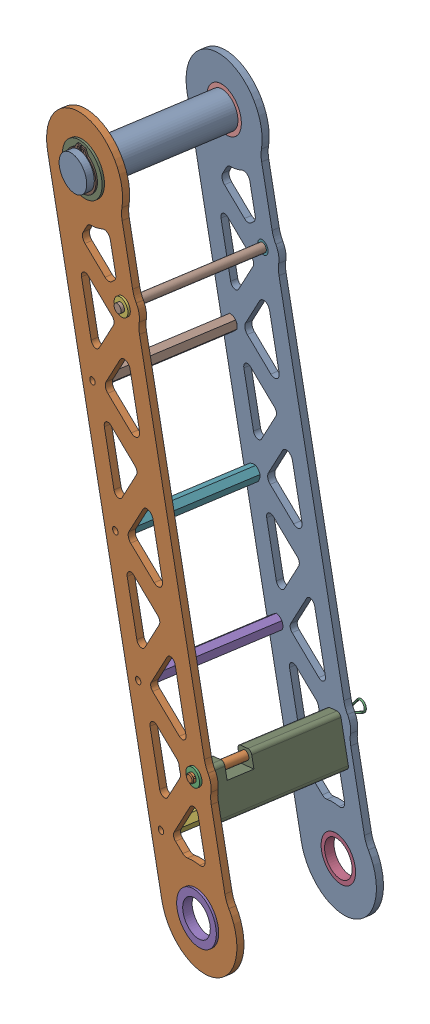
SolidWorks assembly UOR23-ARM-2-A-005_Arm, configuration Default. Lengths in mm.
Overall size (202.51 521.96 130.33).
21 component instances, 9 part files, 41 mates.
Components (placement in the parent):
- UOR23-ARM-2-P-001-1: UOR23-ARM-2-P-001 [Default] at (-90.7389 342.9702 -136.8786) x (-0.230879 0.972312 -0.036117) z (0.154553 0 -0.987984) size (520 70 4.76)
- UOR23-ARM-2-P-001-2: UOR23-ARM-2-P-001 [Default] at (-105.2152 342.9702 -44.3384) x (-0.230879 0.972312 -0.036117) z (0.154553 0 -0.987984) size (520 70 4.76)
- UOR23-ARM-2-P-005-1: UOR23-ARM-2-P-005 [6389K627] at (-56.9045 215.9378 -35.1742) x (-0.987956 0.007597 -0.154549) z (-0.007506 -0.999971 -0.001174) size (12.7 6.35 12.7)
- UOR23-ARM-2-P-005-2: UOR23-ARM-2-P-005 [6389K627] at (-41.2014 215.9378 -135.5565) x (0.894742 -0.424081 0.139967) z (-0.418986 -0.905624 -0.065543) size (12.7 6.35 12.7)
- 91780A086_Female Threaded Hex Standoff-1: 91780A086_Female Threaded Hex Standoff [91780A086] at (-100.8459 249.6199 -93.4658) x (0.375473 0.92497 0.058736) z (-0.154553 0 0.987984) size (9.53 11 89.52)
- 91780A086_Female Threaded Hex Standoff-2: 91780A086_Female Threaded Hex Standoff [91780A086] at (-80.0668 162.1119 -90.2153) x (0.139737 -0.989947 0.021859) z (0.154553 0 -0.987984) size (9.53 11 89.52)
- 91780A086_Female Threaded Hex Standoff-3: 91780A086_Female Threaded Hex Standoff [91780A086] at (-121.625 337.128 -96.7164) x (0.267 -0.962791 0.041768) z (0.154553 0 -0.987984) size (9.53 11 89.52)
- 91780A086_Female Threaded Hex Standoff-4: 91780A086_Female Threaded Hex Standoff [91780A086] at (-142.4041 424.6361 -99.9669) x (0.260385 0.964645 0.040733) z (0.154553 0 -0.987984) size (9.53 11 89.52)
- UOR23-ARM-2-P-007-1: UOR23-ARM-2-P-007 [6389K559] at (-157.4084 561.7403 -50.8963) x (-0.232229 -0.971982 -0.036328) z (0.960303 -0.235054 0.150223) size (36.51 6.35 36.51)
- UOR23-ARM-2-P-007-2: UOR23-ARM-2-P-007 [6389K559] at (-141.7053 561.7403 -151.2787) x (0.987521 0.030636 0.154481) z (0.030268 -0.999531 0.004735) size (36.51 6.35 36.51)
- 98410A133_External Retaining Ring-1: 98410A133_External Retaining Ring [98410A133] at (-157.4908 561.7403 -50.3693) x (-0.154553 0 0.987984) z (-0.987984 0 -0.154553) size (1.07 30.68 28.04)
- 98410A133_External Retaining Ring-2: 98410A133_External Retaining Ring [98410A133] at (-141.6228 561.7403 -151.8056) x (-0.154553 0 0.987984) z (-0.987984 0 -0.154553) size (1.07 30.68 28.04)
- UOR23-ARM-2-P-006-1: UOR23-ARM-2-P-006 [1346K38] at (-187.8474 561.7403 143.6857) x (-0.913412 0.381132 -0.142888) z (0.154553 0 -0.987984) size (25.4 25.4 114.1)
- UOR23-ARM-2-P-008-1: UOR23-ARM-2-P-008 [1327K68] at (-10.1532 215.9378 -334.0329) x (0.513647 -0.854231 0.080351) z (-0.154553 0 0.987984) size (6.35 6.35 106.22)
- 92375A410_Hairpin Cotter Pin-1: 92375A410_Hairpin Cotter Pin [92375A410] at (-40.3363 220.81 -136.2244) x (-0.164223 0.016127 0.986291) z (-0.843967 -0.519894 -0.132024) size (1.19 9.74 41.27)
- UOR23-ARM-2-P-007-3: UOR23-ARM-2-P-007 [6389K559] at (-37.8097 124.2 -135.026) x (-0.957866 -0.245033 -0.149842) z (-0.242089 0.969515 -0.037871) size (36.51 6.35 36.51)
- UOR23-ARM-2-P-007-4: UOR23-ARM-2-P-007 [6389K559] at (-53.5128 124.2 -34.6436) x (0.138917 0.990066 0.021731) z (-0.978169 0.140606 -0.153018) size (36.51 6.35 36.51)
- UOR23-ARM-2-P-005-3: UOR23-ARM-2-P-005 [6389K627] at (-122.1279 490.6159 -45.3772) x (-0.969764 -0.191163 -0.151703) z (0.188866 -0.981558 0.029545) size (12.7 6.35 12.7)
- UOR23-ARM-2-P-005-4: UOR23-ARM-2-P-005 [6389K627] at (-106.4248 490.6159 -145.7596) x (0.656685 -0.747135 0.102727) z (-0.738158 -0.664672 -0.115472) size (12.7 6.35 12.7)
- UOR23-ARM-2-P-008-2: UOR23-ARM-2-P-008 [1327K68] at (-153.1761 490.6159 153.0991) x (0.663492 0.740949 0.103792) z (0.154553 0 -0.987984) size (6.35 6.35 106.22)
- UOR23-ARM-2-P-014-1: UOR23-ARM-2-P-014 [Default] at (-41.501 185.2495 -129.1729) x (0.960629 0.233687 0.150274) z (-0.154553 0 0.987984) size (13 35 88.9)
Mates (geometry in assembly coordinates):
- Concentric27: concentric aligned: circle of UOR23-ARM-2-P-001-1; circle of UOR23-ARM-2-P-001-2
- Coincident203: coincident anti-aligned: plane of UOR23-ARM-2-P-001-2 through (-53.2675 124.2 -36.212) normal (-0.154553 0 0.987984); plane of UOR23-ARM-2-P-005-1 through (-56.6592 215.9378 -36.7426) normal (0.154553 0 -0.987984)
- Concentric207: concentric aligned: circle of UOR23-ARM-2-P-001-2; circle of UOR23-ARM-2-P-005-1
- Coincident197: coincident anti-aligned: plane of UOR23-ARM-2-P-001-1 through (-38.055 124.2 -133.4575) normal (0.154553 0 -0.987984); plane of UOR23-ARM-2-P-005-2 through (-41.4468 215.9378 -133.9881) normal (-0.154553 0 0.987984)
- Concentric200: concentric aligned: circle of UOR23-ARM-2-P-001-1; circle of UOR23-ARM-2-P-005-2
- Concentric197: concentric aligned: circle of UOR23-ARM-2-P-001-1; circle of 91780A086_Female Threaded Hex Standoff-1
- Coincident207: coincident anti-aligned: plane of UOR23-ARM-2-P-001-2 through (-52.5314 124.2 -40.9173) normal (0.154553 0 -0.987984); plane of 91780A086_Female Threaded Hex Standoff-1 through (-112.7413 251.7099 -50.3361) normal (-0.154553 0 0.987984)
- Concentric198: concentric anti-aligned: circle of UOR23-ARM-2-P-001-1; circle of 91780A086_Female Threaded Hex Standoff-2
- Coincident208: coincident anti-aligned: plane of UOR23-ARM-2-P-001-2 through (-52.5314 124.2 -40.9173) normal (0.154553 0 -0.987984); plane of 91780A086_Female Threaded Hex Standoff-2 through (-92.3152 161.3341 -47.1408) normal (-0.154553 0 0.987984)
- Concentric195: concentric anti-aligned: circle of UOR23-ARM-2-P-001-1; circle of 91780A086_Female Threaded Hex Standoff-3
- Coincident206: coincident anti-aligned: plane of UOR23-ARM-2-P-001-2 through (-52.5314 124.2 -40.9173) normal (0.154553 0 -0.987984); plane of 91780A086_Female Threaded Hex Standoff-3 through (-133.7259 335.6418 -53.6188) normal (-0.154553 0 0.987984)
- Concentric196: concentric anti-aligned: circle of UOR23-ARM-2-P-001-1; circle of 91780A086_Female Threaded Hex Standoff-4
- Coincident205: coincident anti-aligned: plane of UOR23-ARM-2-P-001-2 through (-52.5314 124.2 -40.9173) normal (0.154553 0 -0.987984); plane of 91780A086_Female Threaded Hex Standoff-4 through (-144.0329 423.1867 -55.2311) normal (-0.154553 0 0.987984)
- Coincident125: coincident aligned: plane of UOR23-ARM-2-P-006-1 through (-157.4084 561.7403 -50.8963) normal (-0.154553 0 0.987984); plane of UOR23-ARM-2-P-007-1 through (-157.4084 561.7403 -50.8963) normal (-0.154553 0 0.987984)
- Coincident204: coincident anti-aligned: plane of UOR23-ARM-2-P-001-2 through (-53.2675 124.2 -36.212) normal (-0.154553 0 0.987984); plane of UOR23-ARM-2-P-007-1 through (-157.163 561.7403 -52.4647) normal (0.154553 0 -0.987984)
- Concentric209: concentric aligned: circle of UOR23-ARM-2-P-001-2; circle of UOR23-ARM-2-P-007-1
- Coincident134: coincident aligned: plane of UOR23-ARM-2-P-006-1 through (-141.7053 561.7403 -151.2787) normal (0.154553 0 -0.987984); plane of UOR23-ARM-2-P-007-2 through (-141.7053 561.7403 -151.2787) normal (0.154553 0 -0.987984)
- Coincident198: coincident anti-aligned: plane of UOR23-ARM-2-P-001-1 through (-38.055 124.2 -133.4575) normal (0.154553 0 -0.987984); plane of UOR23-ARM-2-P-007-2 through (-141.9506 561.7403 -149.7102) normal (-0.154553 0 0.987984)
- Concentric201: concentric aligned: circle of UOR23-ARM-2-P-001-1; circle of UOR23-ARM-2-P-007-2
- Concentric117: concentric aligned: circle of UOR23-ARM-2-P-006-1; circle of 98410A133_External Retaining Ring-1
- Coincident144: coincident anti-aligned: plane of UOR23-ARM-2-P-006-1 through (-157.4084 561.7403 -50.8963) normal (-0.154553 0 0.987984); plane of 98410A133_External Retaining Ring-1 through (-157.4084 561.7403 -50.8963) normal (0.154553 0 -0.987984)
- Concentric118: concentric aligned: circle of UOR23-ARM-2-P-006-1; circle of 98410A133_External Retaining Ring-2
- Coincident145: coincident anti-aligned: plane of UOR23-ARM-2-P-006-1 through (-141.7053 561.7403 -151.2787) normal (0.154553 0 -0.987984); plane of 98410A133_External Retaining Ring-2 through (-141.7053 561.7403 -151.2787) normal (-0.154553 0 0.987984)
- Concentric194: concentric aligned: circle of UOR23-ARM-2-P-001-1; circle of UOR23-ARM-2-P-006-1
- Concentric205: concentric aligned: circle of UOR23-ARM-2-P-001-2; circle of UOR23-ARM-2-P-006-1
- Concentric120: concentric anti-aligned: cylinder of UOR23-ARM-2-P-008-1 through (-43.7694 214.2871 -136.6893) axis (0.843967 0.519894 0.132024) radius 0.5953; circle of 92375A410_Hairpin Cotter Pin-1
- Tangent1: tangent anti-aligned: cylinder of UOR23-ARM-2-P-008-1 through (-57.261 215.9378 -32.8953) axis (0.154553 0 -0.987984) radius 3.175; torus of 92375A410_Hairpin Cotter Pin-1
- Concentric211: concentric aligned: circle of UOR23-ARM-2-P-005-1; circle of UOR23-ARM-2-P-008-1
- Distance6: distance = 2.3098 mm aligned: plane of UOR23-ARM-2-P-005-2 through (-41.2014 215.9378 -135.5565) normal (0.154553 0 -0.987984); plane of UOR23-ARM-2-P-008-1 through (-40.8444 215.9378 -137.8386) normal (0.154553 0 -0.987984)
- Coincident199: coincident anti-aligned: plane of UOR23-ARM-2-P-001-1 through (-38.055 124.2 -133.4575) normal (0.154553 0 -0.987984); plane of UOR23-ARM-2-P-007-3 through (-38.055 124.2 -133.4575) normal (-0.154553 0 0.987984)
- Concentric202: concentric anti-aligned: circle of UOR23-ARM-2-P-001-1; circle of UOR23-ARM-2-P-007-3
- Coincident209: coincident anti-aligned: plane of UOR23-ARM-2-P-001-2 through (-53.2675 124.2 -36.212) normal (-0.154553 0 0.987984); plane of UOR23-ARM-2-P-007-4 through (-53.2675 124.2 -36.212) normal (0.154553 0 -0.987984)
- Coincident210: coincident anti-aligned: plane of UOR23-ARM-2-P-001-2 through (-53.2675 124.2 -36.212) normal (-0.154553 0 0.987984); plane of UOR23-ARM-2-P-005-3 through (-121.8825 490.6159 -46.9457) normal (0.154553 0 -0.987984)
- Concentric208: concentric aligned: circle of UOR23-ARM-2-P-001-2; circle of UOR23-ARM-2-P-005-3
- Coincident200: coincident anti-aligned: plane of UOR23-ARM-2-P-001-1 through (-38.055 124.2 -133.4575) normal (0.154553 0 -0.987984); plane of UOR23-ARM-2-P-005-4 through (-106.6701 490.6159 -144.1912) normal (-0.154553 0 0.987984)
- Concentric199: concentric aligned: circle of UOR23-ARM-2-P-001-1; circle of UOR23-ARM-2-P-005-4
- Concentric221: concentric anti-aligned: circle of UOR23-ARM-2-P-005-3; circle of UOR23-ARM-2-P-008-2
- Distance8: distance = 2.3098 mm aligned: plane of UOR23-ARM-2-P-005-3 through (-122.1279 490.6159 -45.3772) normal (-0.154553 0 0.987984); plane of UOR23-ARM-2-P-008-2 through (-122.4849 490.6159 -43.0952) normal (-0.154553 0 0.987984)
- Parallel8: parallel aligned: plane of UOR23-ARM-2-P-001-1 through (-13.9997 148.5998 -124.8741) normal (0.960629 0.233687 0.150274); plane of UOR23-ARM-2-P-014-1 through (-42.7527 188.2874 -39.3876) normal (0.960629 0.233687 0.150274)
- Coincident211: coincident anti-aligned: plane of UOR23-ARM-2-P-001-2 through (-52.5314 124.2 -40.9173) normal (0.154553 0 -0.987984); plane of UOR23-ARM-2-P-014-1 through (-55.2408 185.2495 -41.3411) normal (-0.154553 0 0.987984)
- Concentric215: concentric aligned: circle of UOR23-ARM-2-P-008-1; circle of UOR23-ARM-2-P-014-1
